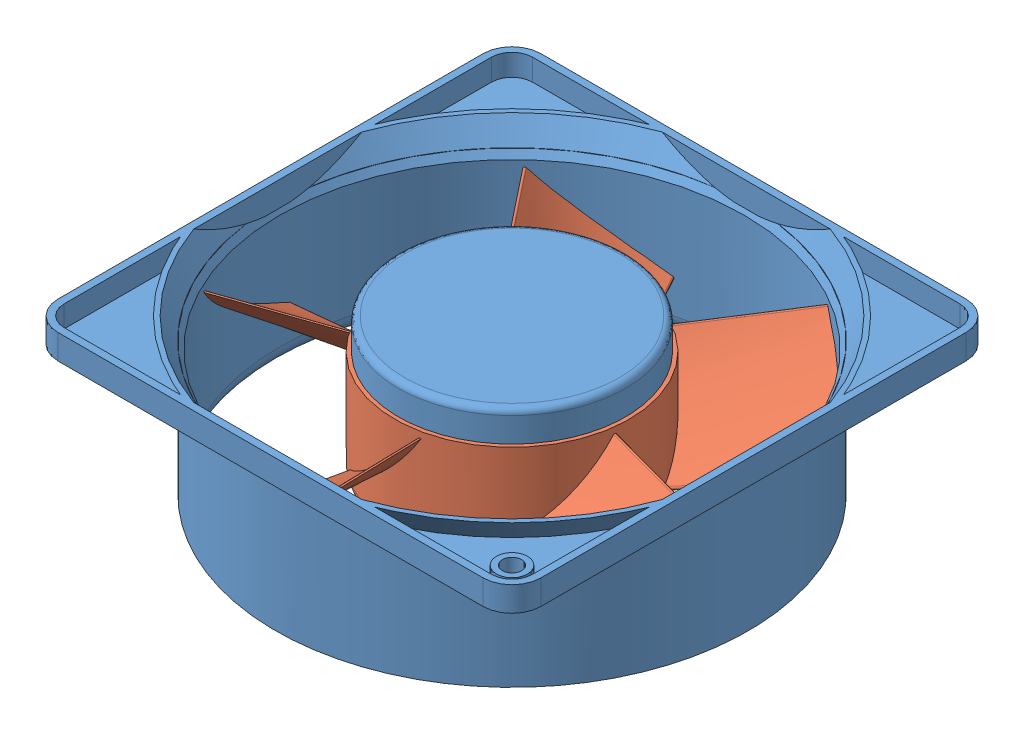
SolidWorks assembly fanlarge_ebmpabst_4212-12h, configuration Default. Lengths in mm.
Overall size (174.69 38.1 174.69).
2 component instances, 2 part files, 0 mates.
Components (placement in the parent):
- Fan Housing-1-1: Fan Housing-1 [Default] at origin size (138.35 38.1 134.46)
- fan-1-1: fan-1 [Default] at (-192.9031 11.4964 -8.5043) x (0.981481 0 0.19156) z (0 -1 0) size (148.92 148.92 26.42)
